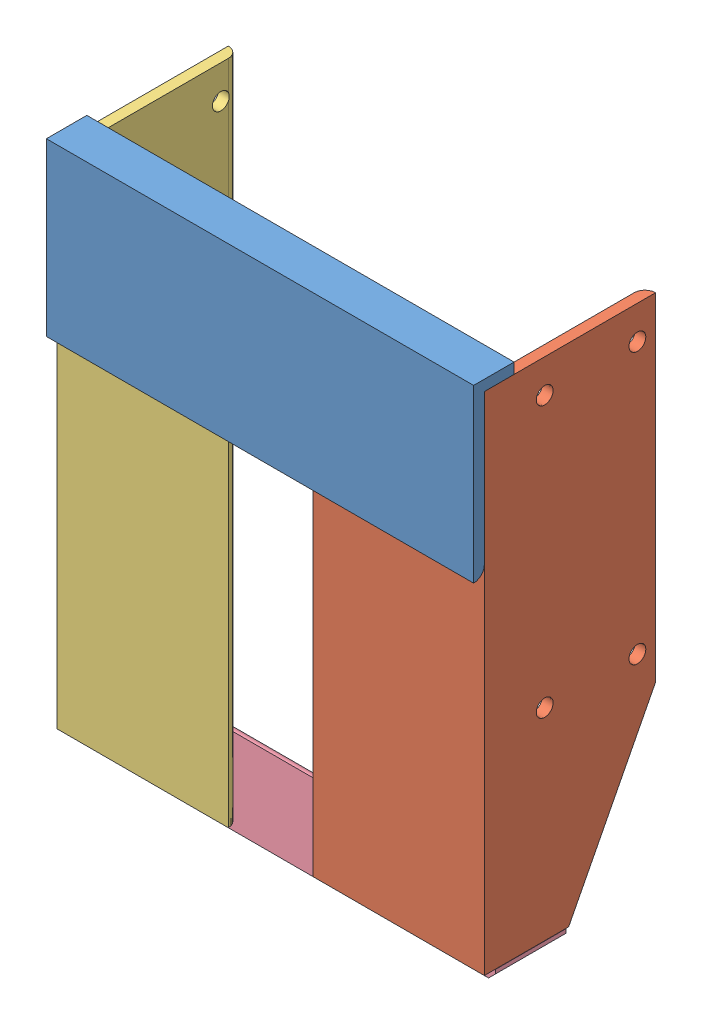
SolidWorks assembly carro eje z, configuration Predeterminado. Lengths in mm.
Overall size (126.87 156.35 53.97).
4 component instances, 4 part files, 9 mates.
Components (placement in the parent):
- soporte tranversal eje z-1: soporte tranversal eje z [Predeterminado<Como mecanizada>] at (-35.1249 73.7249 100.5089) size (126.72 50.8 12)
- viga longitudinal eje z der-1: viga longitudinal eje z der [Predeterminado<Como mecanizada>] at (28.2351 -79.4501 97.3339) x (0 0 -1) z (1 0 0) size (50.8 150 50.8)
- viga longitudinal eje z-1: viga longitudinal eje z [Predeterminado<Como mecanizada>] at (-98.4849 70.5499 97.3339) x (0 0 1) z (1 0 0) size (50.8 150 50.8)
- soporte tranversal inferior eje z-2: soporte tranversal inferior eje z [Predeterminado<Como mecanizada>] at (-35.1249 -82.6251 94.1589) x (1 0 0) z (0 -1 0) size (126.87 21 25.4)
Mates (geometry in assembly coordinates):
- Coincidente1: coincident: plane of assembly; plane of assembly; plane of soporte tranversal eje z-1 through (28.2351 65.7874 97.3339) normal (0 0 -1); plane of viga longitudinal eje z der-1 through (28.2351 70.5499 97.3339) normal (0 0 1)
- Coincidente2: coincident: plane of assembly; plane of assembly; plane of soporte tranversal eje z-1 through (28.2351 73.7199 52.8788) normal (1 0 0); plane of viga longitudinal eje z der-1 through (28.2351 70.5499 46.5339) normal (1 0 0)
- Coincidente3: coincident: plane of assembly; plane of assembly; plane of soporte tranversal eje z-1 through (28.2351 70.5499 52.8788) normal (0 -1 0); plane of viga longitudinal eje z der-1 through (-19.395 70.5499 97.3288) normal (0 1 0)
- Coincidente4: coincident: plane of assembly; plane of assembly; plane of soporte tranversal eje z-1 through (28.2351 65.7874 97.3339) normal (0 0 -1); plane of viga longitudinal eje z-1 through (-98.4849 -79.4501 97.3339) normal (0 0 1)
- Coincidente5: coincident: plane of assembly; plane of assembly; plane of soporte tranversal eje z-1 through (-98.4849 73.7199 52.8788) normal (-1 0 0); plane of viga longitudinal eje z-1 through (-98.4849 -79.4501 46.5339) normal (-1 0 0)
- Coincidente6: coincident: plane of assembly; plane of assembly; plane of soporte tranversal eje z-1 through (28.2351 70.5499 52.8788) normal (0 -1 0); plane of viga longitudinal eje z-1 through (-50.8549 70.5499 97.3288) normal (0 1 0)
- Coincidente7: coincident: plane of assembly; plane of assembly; plane of viga longitudinal eje z der-1 through (-19.395 70.5499 94.1589) normal (0 0 -1); plane of soporte tranversal inferior eje z-2 through (28.3101 -82.6251 94.1589) normal (0 0 1)
- Coincidente8: coincident: plane of assembly; plane of assembly; plane of viga longitudinal eje z-1 through (-95.3099 -79.4501 89.3964) normal (1 0 0); plane of soporte tranversal inferior eje z-2 through (-95.3099 -82.6251 84.1589) normal (-1 0 0)
- Coincidente9: coincident: plane of assembly; plane of assembly; plane of viga longitudinal eje z-1 through (-50.8549 -79.4501 97.3288) normal (0 -1 0); plane of soporte tranversal inferior eje z-2 through (28.3101 -79.4501 86.2214) normal (0 1 0)
